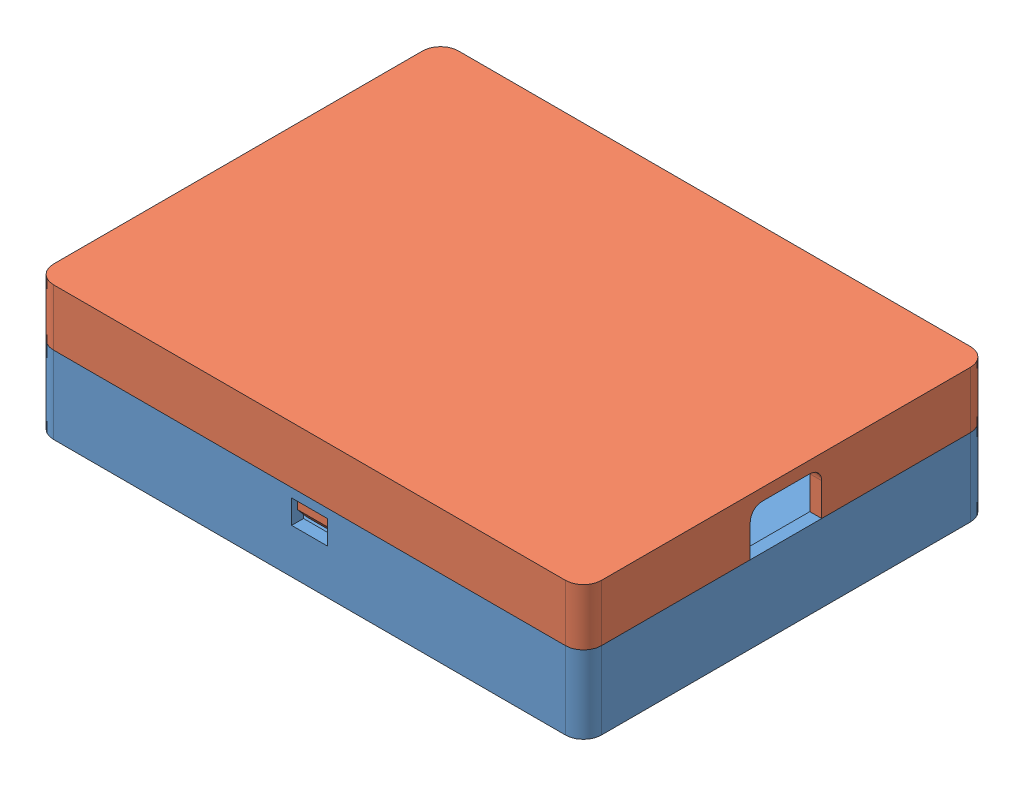
SolidWorks assembly red_bear_enclosure_assy, configuration Default. Lengths in mm.
Overall size (92 22.5 68).
2 component instances, 2 part files, 3 mates.
Components (placement in the parent):
- case_base-1: case_base [Default] at origin size (92 13 68)
- case_lid-1: case_lid [Default] at (0 22.5 0) x (1 0 0) z (0 0 -1) size (92 14.5 68)
Mates (geometry in assembly coordinates):
- Coincident1: coincident anti-aligned: plane of case_base-1 through (0 13 0) normal (0 1 0); plane of case_lid-1 through (0 13 0) normal (0 -1 0)
- Coincident2: coincident aligned: plane of case_base-1 through (46 13 -34) normal (1 0 0); plane of case_lid-1 through (46 13 34) normal (1 0 0)
- Coincident3: coincident aligned: plane of case_base-1 through (-46 13 -34) normal (0 0 -1); plane of case_lid-1 through (-46 13 -34) normal (0 0 -1)
